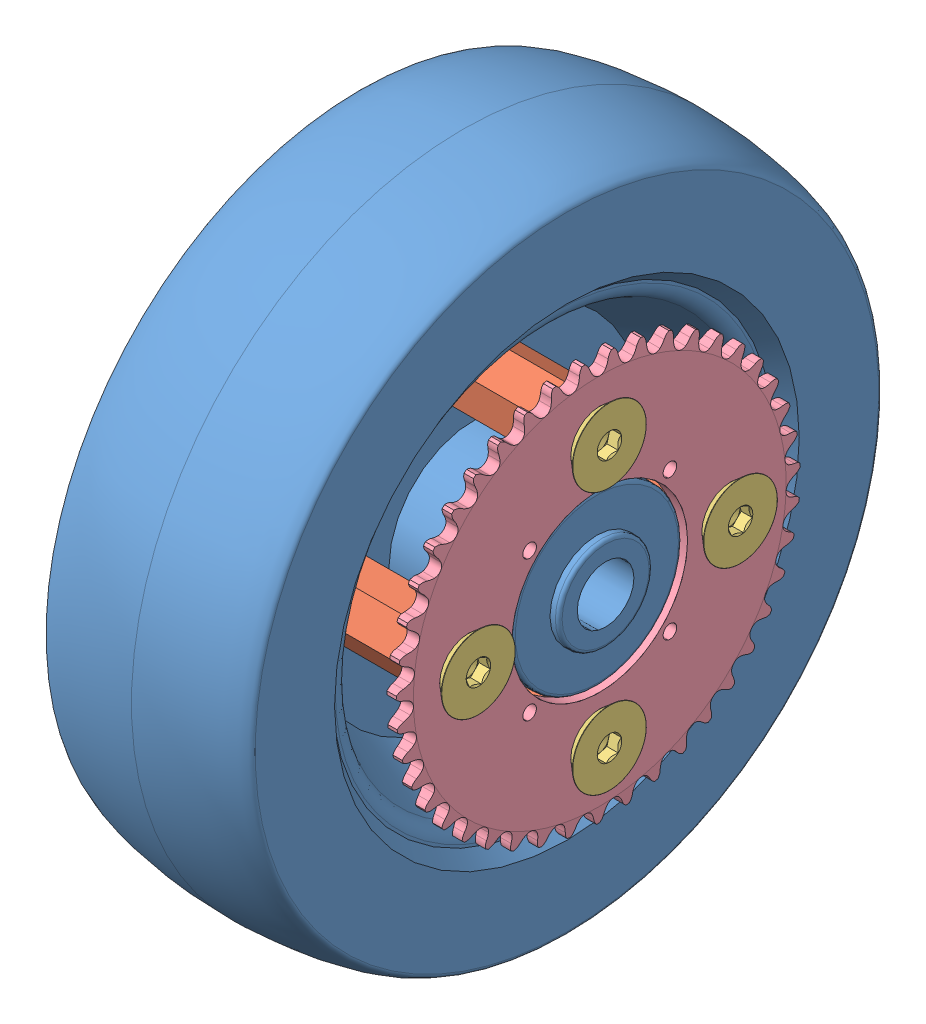
SolidWorks assembly wheel-gear, configuration Default. Lengths in mm.
Overall size (65.05 148.59 148.59).
10 component instances, 4 part files, 6 mates.
Components (placement in the parent):
- wheel-1: wheel [Default] at (-54.8557 -0.5385 29.3125) size (63.91 148.59 148.59)
- wheel-standoff-1: wheel-standoff [Default] at (-27.0046 -29.9073 29.3125) x (0 1 0) z (0 0 1) size (14.66 25.4 12.7)
- screw-wheel-2-1: screw-wheel-2 [91253A578] at (-27.059 -29.9073 29.3125) x (0 -0.706923 0.70729) z (1 0 0) size (16.54 16.54 13)
- screw-wheel-2-3: screw-wheel-2 [91253A578] at (-27.059 -0.5385 58.6812) x (0 0.70729 0.706923) z (1 0 0) size (16.54 16.54 13)
- screw-wheel-2-4: screw-wheel-2 [91253A578] at (-27.059 28.8302 29.3125) x (0 0.706923 -0.70729) z (1 0 0) size (16.54 16.54 13)
- screw-wheel-2-5: screw-wheel-2 [91253A578] at (-27.059 -0.5385 -0.0563) x (0 -0.70729 -0.706923) z (1 0 0) size (16.54 16.54 13)
- wheel-standoff-5: wheel-standoff [Default] at (-27.0046 -0.5385 58.6812) x (0 0 -1) z (0 1 0) size (14.66 25.4 12.7)
- wheel-standoff-6: wheel-standoff [Default] at (-27.0046 28.8302 29.3125) x (0 -1 0) z (0 0 -1) size (14.66 25.4 12.7)
- wheel-standoff-7: wheel-standoff [Default] at (-27.0046 -0.5385 -0.0563) x (0 0 1) z (0 -1 0) size (14.66 25.4 12.7)
- sprocket-wheel-43-2: sprocket-wheel-43 [Default] at (-25.6076 -0.5385 29.3125) x (0 0 -1) z (1 0 0) size (90.54 90.48 2.81)
Mates (geometry in assembly coordinates):
- Coincident1: coincident anti-aligned: plane of wheel-1 through (-52.4046 -0.5385 29.3125) normal (1 0 0); plane of wheel-standoff-1 through (-52.4046 -22.5749 29.3125) normal (-1 0 0)
- Concentric3: concentric aligned: cylinder of wheel-1 through (-86.8089 -29.9073 29.3125) axis (1 0 0) radius 3.9688; cylinder of wheel-standoff-1 through (-52.4046 -29.9073 29.3125) axis (1 0 0) radius 3.3528
- Coincident4: coincident anti-aligned: plane of wheel-standoff-7 through (-27.0046 -0.5385 7.2761) normal (1 0 0); plane of sprocket-wheel-43-2 through (-27.0046 -0.5385 29.3125) normal (-1 0 0)
- Concentric8: concentric aligned: cylinder of wheel-1 through (-24.8583 -0.5385 29.3125) axis (-1 0 0) radius 19.05; cylinder of sprocket-wheel-43-2 through (-27.0046 -0.5385 29.3125) axis (-1 0 0) radius 19.685
- Concentric9: concentric aligned: cylinder of wheel-standoff-1 through (-52.4046 -29.9073 29.3125) axis (1 0 0) radius 3.3528; cylinder of sprocket-wheel-43-2 through (-27.0107 -29.9073 29.3125) axis (1 0 0) radius 3.9688
- Concentric10: concentric aligned: cone of screw-wheel-2-4 through (-22.0298 28.8302 29.3125) axis (-1 0 0); cone of sprocket-wheel-43-2 through (-26.4186 28.8302 29.3125) axis (-1 0 0)
